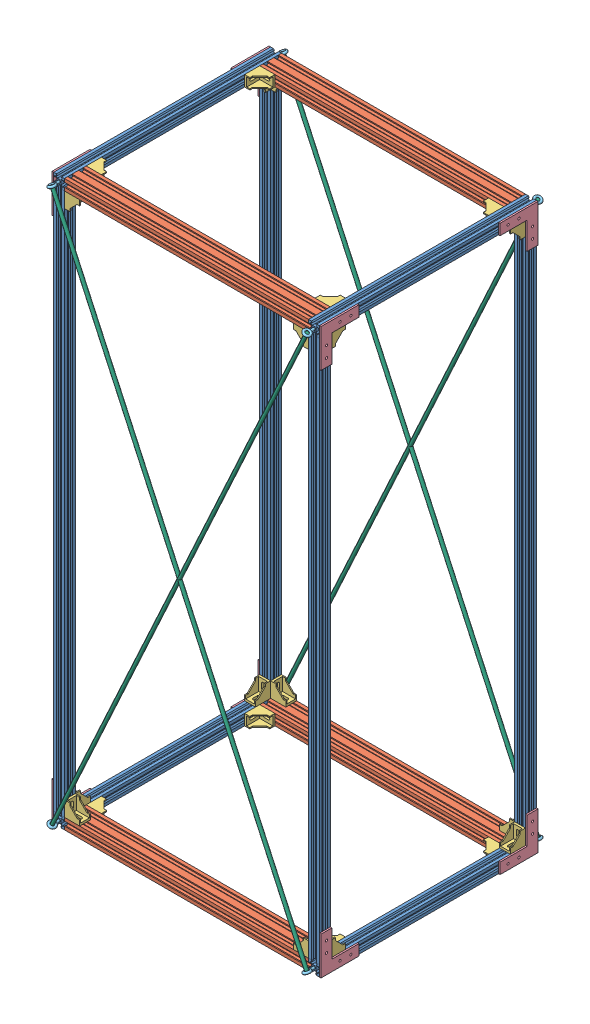
SolidWorks assembly Torre, configuration Valor predeterminado. Lengths in mm.
Overall size (496 1040 439.8).
58 component instances, 6 part files, 43 mates.
Components (placement in the parent):
- Quadrado_400x490mm-1: Quadrado_400x490mm [Valor predeterminado] at (785.4581 775.4893 275.5057) size (490 20 400)
  - Perfil_20x20mm-3: Perfil_20x20mm [400mm] at (-555.9529 400 -177.9915) x (1 0 0) z (0 -1 0) size (20 400 20)
  - Perfil_20x40mm-2: Perfil_20x40mm [450mm] at (-545.9529 400 -147.9915) x (0 0 -1) z (0 -1 0) size (40 450 20)
  - Perfil_20x40mm-3: Perfil_20x40mm [450mm] at (-545.9529 400 212.0085) x (0 0 -1) z (0 -1 0) size (40 450 20)
  - Perfil_20x20mm-4: Perfil_20x20mm [400mm] at (-85.9529 400 -177.9915) x (1 0 0) z (0 -1 0) size (20 400 20)
  - Cantoneira_interna_20x20mm-1: Cantoneira_interna_20x20mm [Default] at (-95.9529 390 182.0085) x (0 1 0) z (0 0 1) size (20 28 28)
  - Cantoneira_interna_20x20mm-2: Cantoneira_interna_20x20mm [Default] at (-95.9529 410 -137.9915) x (0 -1 0) z (0 0 -1) size (20 28 28)
  - Cantoneira_interna_20x20mm-3: Cantoneira_interna_20x20mm [Default] at (-545.9529 390 -137.9915) x (0 1 0) z (0 0 -1) size (20 28 28)
  - Cantoneira_interna_20x20mm-4: Cantoneira_interna_20x20mm [Default] at (-545.9529 410 182.0085) x (0 -1 0) z (0 0 1) size (20 28 28)
- Quadrado_400x490mm-2: Quadrado_400x490mm [Valor predeterminado] at (785.4581 -244.5107 275.5057) size (490 20 400)
  - Perfil_20x20mm-3: Perfil_20x20mm [400mm] at (-555.9529 400 -177.9915) x (1 0 0) z (0 -1 0) size (20 400 20)
  - Perfil_20x40mm-2: Perfil_20x40mm [450mm] at (-545.9529 400 -147.9915) x (0 0 -1) z (0 -1 0) size (40 450 20)
  - Perfil_20x40mm-3: Perfil_20x40mm [450mm] at (-545.9529 400 212.0085) x (0 0 -1) z (0 -1 0) size (40 450 20)
  - Perfil_20x20mm-4: Perfil_20x20mm [400mm] at (-85.9529 400 -177.9915) x (1 0 0) z (0 -1 0) size (20 400 20)
  - Cantoneira_interna_20x20mm-1: Cantoneira_interna_20x20mm [Default] at (-95.9529 390 182.0085) x (0 1 0) z (0 0 1) size (20 28 28)
  - Cantoneira_interna_20x20mm-2: Cantoneira_interna_20x20mm [Default] at (-95.9529 410 -137.9915) x (0 -1 0) z (0 0 -1) size (20 28 28)
  - Cantoneira_interna_20x20mm-3: Cantoneira_interna_20x20mm [Default] at (-545.9529 390 -137.9915) x (0 1 0) z (0 0 -1) size (20 28 28)
  - Cantoneira_interna_20x20mm-4: Cantoneira_interna_20x20mm [Default] at (-545.9529 410 182.0085) x (0 -1 0) z (0 0 1) size (20 28 28)
- Perfil_20x20mm-1: Perfil_20x20mm [1000mm] at (699.5052 165.4893 487.5141) size (20 1000 20)
- Perfil_20x20mm-2: Perfil_20x20mm [1000mm] at (699.5052 1165.4893 107.5141) x (1 0 0) z (0 0 -1) size (20 1000 20)
- Perfil_20x20mm-3: Perfil_20x20mm [1000mm] at (229.5052 1165.4893 487.5141) x (-1 0 0) z (0 0 1) size (20 1000 20)
- Perfil_20x20mm-4: Perfil_20x20mm [1000mm] at (229.5052 165.4893 107.5141) x (-1 0 0) z (0 0 -1) size (20 1000 20)
- Cantoneira_interna_20x20mm-1: Cantoneira_interna_20x20mm [Default] at (689.5052 165.4893 477.5141) size (20 28 28)
- Cantoneira_interna_20x20mm-2: Cantoneira_interna_20x20mm [Default] at (689.5052 165.4893 477.5141) x (0 0 1) z (0 -1 0) size (20 28 28)
- Cantoneira_plana_lateral-3: Cantoneira_plana_lateral [Valor predeterminado] at (709.5052 145.4893 497.5141) size (3 70 70)
- Cantoneira_interna_20x20mm-3: Cantoneira_interna_20x20mm [Default] at (689.5052 165.4893 97.5141) x (0 0 1) z (0 -1 0) size (20 28 28)
- Cantoneira_interna_20x20mm-4: Cantoneira_interna_20x20mm [Default] at (709.5052 165.4893 117.5141) x (-1 0 0) z (0 0 -1) size (20 28 28)
- Cantoneira_interna_20x20mm-5: Cantoneira_interna_20x20mm [Default] at (239.5052 165.4893 497.5141) x (0 0 -1) z (0 -1 0) size (20 28 28)
- Cantoneira_interna_20x20mm-6: Cantoneira_interna_20x20mm [Default] at (219.5052 165.4893 477.5141) size (20 28 28)
- Cantoneira_interna_20x20mm-7: Cantoneira_interna_20x20mm [Default] at (239.5052 165.4893 117.5141) x (-1 0 0) z (0 0 -1) size (20 28 28)
- Cantoneira_interna_20x20mm-8: Cantoneira_interna_20x20mm [Default] at (239.5052 165.4893 117.5141) x (0 0 -1) z (0 -1 0) size (20 28 28)
- Cantoneira_interna_20x20mm-9: Cantoneira_interna_20x20mm [Default] at (709.5052 1165.4893 477.5141) x (-1 0 0) z (0 0 1) size (20 28 28)
- Cantoneira_interna_20x20mm-10: Cantoneira_interna_20x20mm [Default] at (689.5052 1165.4893 497.5141) x (0 0 -1) z (0 1 0) size (20 28 28)
- Cantoneira_interna_20x20mm-11: Cantoneira_interna_20x20mm [Default] at (689.5052 1165.4893 117.5141) x (0 0 -1) z (0 1 0) size (20 28 28)
- Cantoneira_interna_20x20mm-12: Cantoneira_interna_20x20mm [Default] at (689.5052 1165.4893 117.5141) x (1 0 0) z (0 0 -1) size (20 28 28)
- Cantoneira_interna_20x20mm-13: Cantoneira_interna_20x20mm [Default] at (239.5052 1165.4893 477.5141) x (0 0 1) z (0 1 0) size (20 28 28)
- Cantoneira_interna_20x20mm-14: Cantoneira_interna_20x20mm [Default] at (239.5052 1165.4893 477.5141) x (-1 0 0) z (0 0 1) size (20 28 28)
- Cantoneira_interna_20x20mm-15: Cantoneira_interna_20x20mm [Default] at (239.5052 1165.4893 97.5141) x (0 0 1) z (0 1 0) size (20 28 28)
- Cantoneira_interna_20x20mm-16: Cantoneira_interna_20x20mm [Default] at (219.5052 1165.4893 117.5141) x (1 0 0) z (0 0 -1) size (20 28 28)
- Cantoneira_plana_lateral-6: Cantoneira_plana_lateral [Valor predeterminado] at (712.5052 145.4893 97.5141) x (-1 0 0) z (0 0 -1) size (3 70 70)
- Cantoneira_plana_lateral-8: Cantoneira_plana_lateral [Valor predeterminado] at (216.5052 145.4893 497.5141) size (3 70 70)
- Cantoneira_plana_lateral-10: Cantoneira_plana_lateral [Valor predeterminado] at (219.5052 145.4893 97.5141) x (-1 0 0) z (0 0 -1) size (3 70 70)
- Cantoneira_plana_lateral-12: Cantoneira_plana_lateral [Valor predeterminado] at (712.5052 1185.4893 497.5141) x (-1 0 0) z (0 0 1) size (3 70 70)
- Cantoneira_plana_lateral-13: Cantoneira_plana_lateral [Valor predeterminado] at (709.5052 1185.4893 97.5141) x (1 0 0) z (0 0 -1) size (3 70 70)
- Cantoneira_plana_lateral-15: Cantoneira_plana_lateral [Valor predeterminado] at (219.5052 1185.4893 497.5141) x (-1 0 0) z (0 0 1) size (3 70 70)
- Cantoneira_plana_lateral-17: Cantoneira_plana_lateral [Valor predeterminado] at (216.5052 1185.4893 97.5141) x (1 0 0) z (0 0 -1) size (3 70 70)
- Parafuso_Olhal_30mm-1: Parafuso_Olhal_30mm [Valor predeterminado] at (699.5052 155.4893 510.2646) x (-0.418493 0.90822 0) z (0.90822 0.418493 0) size (4.3 42.15 14.3)
- Cabo_de_aco-1: Cabo_de_aco [Valor predeterminado] at (699.8354 154.7727 510.2646) x (-0.296683 -0.136707 0.94514) z (-0.858395 -0.395535 -0.326665) size (6 1124 6)
- Parafuso_Olhal_30mm-2: Parafuso_Olhal_30mm [Valor predeterminado] at (699.5052 155.4893 84.7636) x (0.418493 -0.90822 0) z (0.90822 0.418493 0) size (4.3 42.15 14.3)
- Parafuso_Olhal_30mm-3: Parafuso_Olhal_30mm [Valor predeterminado] at (229.5052 155.4893 510.2646) x (-0.418493 -0.90822 0) z (-0.90822 0.418493 0) size (4.3 42.15 14.3)
- Parafuso_Olhal_30mm-4: Parafuso_Olhal_30mm [Valor predeterminado] at (229.5052 155.4893 84.7636) x (0.418493 0.90822 0) z (-0.90822 0.418493 0) size (4.3 42.15 14.3)
- Parafuso_Olhal_30mm-5: Parafuso_Olhal_30mm [Valor predeterminado] at (699.5052 1175.4893 510.2646) x (0.418493 0.90822 0) z (0.90822 -0.418493 0) size (4.3 42.15 14.3)
- Parafuso_Olhal_30mm-6: Parafuso_Olhal_30mm [Valor predeterminado] at (699.5052 1175.4893 84.7636) x (-0.418493 -0.90822 0) z (0.90822 -0.418493 0) size (4.3 42.15 14.3)
- Parafuso_Olhal_30mm-7: Parafuso_Olhal_30mm [Valor predeterminado] at (229.5052 1175.4893 84.7636) x (-0.418493 0.90822 0) z (-0.90822 -0.418493 0) size (4.3 42.15 14.3)
- Parafuso_Olhal_30mm-8: Parafuso_Olhal_30mm [Valor predeterminado] at (229.5052 1175.4893 510.2646) x (0.418493 -0.90822 0) z (-0.90822 -0.418493 0) size (4.3 42.15 14.3)
- Cabo_de_aco-2: Cabo_de_aco [Valor predeterminado] at (699.8354 154.7727 84.7636) x (-0.296683 -0.136707 -0.94514) z (0.858395 0.395535 -0.326665) size (6 1124 6)
- Cabo_de_aco-3: Cabo_de_aco [Valor predeterminado] at (229.175 154.7727 510.2646) x (0.296683 -0.136707 0.94514) z (-0.858395 0.395535 0.326665) size (6 1124 6)
- Cabo_de_aco-4: Cabo_de_aco [Valor predeterminado] at (229.175 154.7727 84.7636) x (0.296683 -0.136707 -0.94514) z (0.858395 -0.395535 0.326665) size (6 1124 6)
Mates (geometry in assembly coordinates):
- Coincidente1: coincident aligned: plane of ? through (712.8098 135.5054 490.8743) normal (1 0 0); plane of ? through (712.8098 1155.5054 490.8743) normal (1 0 0)
- Coincidente2: coincident aligned: plane of ? through (692.8098 131.5054 490.8743) normal (0 0 1); plane of ? through (692.8098 1151.5054 490.8743) normal (0 0 1)
- Coincidente3: coincident aligned: plane of ? through (712.8098 135.5054 490.8743) normal (1 0 0); plane of Perfil_20x20mm-1 through (712.8098 1145.5054 480.8743) normal (1 0 0)
- Coincidente4: coincident aligned: plane of ? through (692.8098 145.5054 490.8743) normal (0 0 1); plane of Perfil_20x20mm-1 through (702.8098 1145.5054 490.8743) normal (0 0 1)
- Coincidente5: coincident anti-aligned: plane of ? through (702.8098 145.5054 490.8743) normal (0 1 0); plane of Perfil_20x20mm-1 through (702.8098 145.5054 480.8743) normal (0 -1 0)
- Coincidente6: coincident anti-aligned: plane of ? through (702.8098 1145.5054 490.8743) normal (0 -1 0); plane of Perfil_20x20mm-1 through (702.8098 1145.5054 480.8743) normal (0 1 0)
- Coincidente7: coincident anti-aligned: plane of ? through (702.8098 145.5054 490.8743) normal (0 1 0); plane of Cantoneira_interna_20x20mm-1 through (712.8098 145.5054 470.8743) normal (0 -1 0)
- Coincidente9: coincident anti-aligned: plane of Perfil_20x20mm-1 through (699.5052 1165.4893 477.5141) normal (0 0 -1); plane of Cantoneira_interna_20x20mm-1 through (709.5052 165.4893 477.5141) normal (0 0 1)
- Coincidente10: coincident aligned: plane of Perfil_20x20mm-1 through (709.5052 1165.4893 487.5141) normal (1 0 0); plane of Cantoneira_interna_20x20mm-1 through (709.5052 165.4893 477.5141) normal (1 0 0)
- Coincidente11: coincident anti-aligned: plane of ? through (692.8098 145.5054 490.8743) normal (0 1 0); plane of Cantoneira_interna_20x20mm-2 through (692.8098 145.5054 490.8743) normal (0 -1 0)
- Coincidente12: coincident anti-aligned: plane of Perfil_20x20mm-1 through (689.5052 1165.4893 487.5141) normal (-1 0 0); plane of Cantoneira_interna_20x20mm-2 through (689.5052 165.4893 497.5141) normal (1 0 0)
- Coincidente13: coincident aligned: plane of Perfil_20x20mm-1 through (699.5052 1165.4893 497.5141) normal (0 0 1); plane of Cantoneira_interna_20x20mm-2 through (689.5052 165.4893 497.5141) normal (0 0 1)
- Coincidente14: coincident aligned: plane of Cantoneira_interna_20x20mm-9 through (709.5052 1165.4893 477.5141) normal (1 0 0); plane of Quadrado_400x490mm-1/Perfil_20x20mm-4 through (709.5052 1175.4893 497.5141) normal (1 0 0)
- Coincidente15: coincident aligned: plane of Cantoneira_interna_20x20mm-10 through (689.5052 1165.4893 497.5141) normal (0 0 1); plane of Quadrado_400x490mm-1/Perfil_20x40mm-3 through (689.5052 1171.4893 497.5141) normal (0 0 1)
- Coincidente16: coincident anti-aligned: plane of Cantoneira_interna_20x20mm-9 through (689.5052 1165.4893 477.5141) normal (0 1 0); plane of Quadrado_400x490mm-1/Perfil_20x20mm-4 through (699.5052 1165.4893 497.5141) normal (0 -1 0)
- Coincidente17: coincident aligned: plane of Cantoneira_interna_20x20mm-2 through (689.5052 165.4893 497.5141) normal (0 0 1); plane of Quadrado_400x490mm-2/Perfil_20x40mm-3 through (689.5052 165.4893 497.5141) normal (0 0 1)
- Coincidente18: coincident aligned: plane of Cantoneira_interna_20x20mm-1 through (709.5052 165.4893 477.5141) normal (1 0 0); plane of Quadrado_400x490mm-2/Perfil_20x20mm-4 through (709.5052 155.4893 497.5141) normal (1 0 0)
- Coincidente19: coincident anti-aligned: plane of Cantoneira_interna_20x20mm-1 through (709.5052 165.4893 477.5141) normal (0 -1 0); plane of Quadrado_400x490mm-2/Perfil_20x20mm-4 through (699.5052 165.4893 497.5141) normal (0 1 0)
- Coincidente20: coincident anti-aligned: plane of Perfil_20x20mm-1 through (699.5052 1165.4893 477.5141) normal (0 0 -1); plane of Cantoneira_interna_20x20mm-9 through (689.5052 1165.4893 477.5141) normal (0 0 1)
- Coincidente21: coincident anti-aligned: plane of Perfil_20x20mm-1 through (689.5052 1165.4893 487.5141) normal (-1 0 0); plane of Cantoneira_interna_20x20mm-10 through (689.5052 1165.4893 477.5141) normal (1 0 0)
- Coincidente22: coincident anti-aligned: plane of Quadrado_400x490mm-1/Perfil_20x20mm-4 through (699.5052 1165.4893 497.5141) normal (0 -1 0); plane of Perfil_20x20mm-1 through (699.5052 1165.4893 487.5141) normal (0 1 0)
- Coincidente23: coincident aligned: plane of Perfil_20x20mm-1 through (699.5052 1165.4893 487.5141) normal (0 1 0); plane of Cantoneira_interna_20x20mm-10 through (689.5052 1165.4893 477.5141) normal (0 1 0)
- Coincidente24: coincident anti-aligned: plane of Quadrado_400x490mm-2/Perfil_20x20mm-4 through (699.5052 165.4893 497.5141) normal (0 1 0); plane of Perfil_20x20mm-1 through (699.5052 165.4893 487.5141) normal (0 -1 0)
- Coincidente25: coincident aligned: plane of Quadrado_400x490mm-1/Perfil_20x20mm-4 through (699.5052 1185.4893 497.5141) normal (0 1 0); plane of ? through (712.5052 1185.4893 497.5141) normal (0 1 0)
- Coincidente26: coincident aligned: plane of Perfil_20x20mm-1 through (699.5052 1165.4893 497.5141) normal (0 0 1); plane of ? through (712.5052 1185.4893 497.5141) normal (0 0 1)
- Coincidente27: coincident anti-aligned: plane of Quadrado_400x490mm-1/Perfil_20x20mm-4 through (709.5052 1175.4893 497.5141) normal (1 0 0); plane of ? through (709.5052 1185.4893 497.5141) normal (-1 0 0)
- Coincidente29: coincident aligned: plane of Quadrado_400x490mm-1/Perfil_20x40mm-3 through (689.5052 1185.4893 497.5141) normal (0 1 0); plane of ? through (709.5052 1185.4893 537.1623) normal (0 1 0)
- Coincidente30: coincident aligned: plane of Perfil_20x20mm-1 through (709.5052 1165.4893 487.5141) normal (1 0 0); plane of ? through (709.5052 1185.4893 537.1623) normal (1 0 0)
- Coincidente31: coincident anti-aligned: plane of Quadrado_400x490mm-1/Perfil_20x40mm-3 through (689.5052 1185.4893 497.5141) normal (0 0 1); plane of ? through (709.5052 1185.4893 497.5141) normal (0 0 -1)
- Coincidente32: coincident aligned: plane of Perfil_20x20mm-1 through (699.5052 1165.4893 497.5141) normal (0 0 1); plane of Cantoneira_plana_lateral-3 through (712.5052 145.4893 497.5141) normal (0 0 1)
- Coincidente33: coincident anti-aligned: plane of Quadrado_400x490mm-2/Perfil_20x20mm-4 through (709.5052 155.4893 497.5141) normal (1 0 0); plane of Cantoneira_plana_lateral-3 through (709.5052 145.4893 497.5141) normal (-1 0 0)
- Coincidente34: coincident aligned: plane of Quadrado_400x490mm-2/Perfil_20x20mm-4 through (699.5052 145.4893 497.5141) normal (0 -1 0); plane of Cantoneira_plana_lateral-3 through (712.5052 145.4893 497.5141) normal (0 -1 0)
- Coincidente35: coincident anti-aligned: plane of Perfil_20x20mm-1 through (699.5052 1165.4893 497.5141) normal (0 0 1); plane of ? through (709.5052 145.4893 497.5141) normal (0 0 -1)
- Coincidente36: coincident aligned: plane of Perfil_20x20mm-1 through (709.5052 1165.4893 487.5141) normal (1 0 0); plane of ? through (709.5052 145.4893 497.5141) normal (1 0 0)
- Coincidente37: coincident aligned: plane of Quadrado_400x490mm-2/Perfil_20x40mm-3 through (689.5052 145.4893 497.5141) normal (0 -1 0); plane of ? through (709.5052 145.4893 497.5141) normal (0 -1 0)
- Concêntrico2: concentric aligned: cylinder of Quadrado_400x490mm-2/Perfil_20x20mm-4 through (699.5052 155.4893 497.5141) axis (0 0 -1) radius 2.1; cylinder of Parafuso_Olhal_30mm-1 through (699.5052 155.4893 505.2646) axis (0 0 -1) radius 2.15
- No local1: in place: plane of ? through (0 0 506.6711) normal (0 0 1); moOrthogonalPlaneRef_w of ? through (0 0 506.6711) normal (0 1 0); plane of ? through (0 0 506.6711) normal (1 0 0); unknown of ?
- Coincidente38: coincident aligned: plane of ?; plane of assembly
- Coincidente39: coincident aligned: plane of ? through (0 0 506.6711) normal (0 1 0)
- Coincidente40: coincident anti-aligned: plane of ? through (0 0 506.6711) normal (1 0 0)
- Concêntrico5: concentric anti-aligned: cylinder of Parafuso_Olhal_30mm-1 through (700.4049 153.5366 510.2646) axis (-0.418493 0.90822 0) radius 3; cylinder of Parafuso_Olhal_30mm-8 through (228.6054 1177.442 510.2646) axis (0.418493 -0.90822 0) radius 3
- Concêntrico6: concentric aligned: cylinder of Parafuso_Olhal_30mm-8 through (228.6054 1177.442 510.2646) axis (0.418493 -0.90822 0) radius 3; cylinder of Cabo_de_aco-1 through (229.4487 1175.6118 510.2646) axis (0.418493 -0.90822 0) radius 3
- Coincidente40: coincident anti-aligned: circle of Parafuso_Olhal_30mm-1; circle of Cabo_de_aco-1
